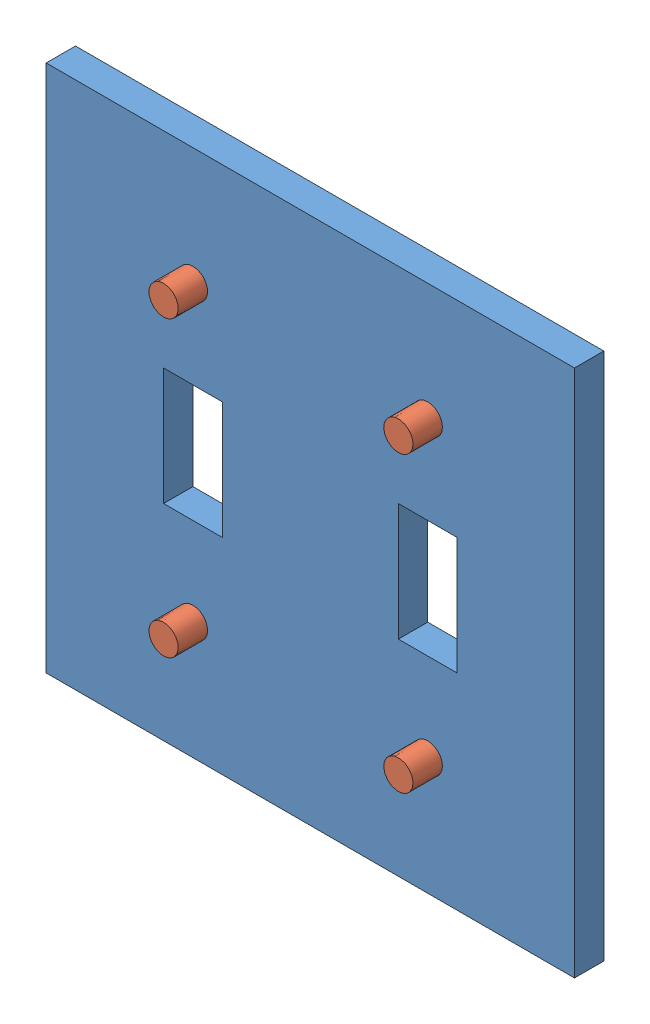
SolidWorks assembly switchplateassembly, configuration Default. Lengths in mm.
Overall size (114.3 114.3 19.05).
5 component instances, 2 part files, 8 mates.
Components (placement in the parent):
- switchplate-2: switchplate [Default] at (-12.9603 3.888 82.8112) size (114.3 114.3 6.35)
- fastener-1: fastener [Default] at (14.7933 100.83 76.4612) x (-0.318546 -0.947907 0) z (0 0 1) size (12.7 12.7 19.05)
- fastener-2: fastener [Default] at (66.8696 37.8464 76.4612) x (-0.459707 -0.88807 0) z (0 0 1) size (12.7 12.7 19.05)
- fastener-3: fastener [Default] at (23.1681 21.4474 76.4612) x (0.272622 0.962121 0) z (0 0 1) size (12.7 12.7 19.05)
- fastener-4: fastener [Default] at (69.3542 83.8108 76.4612) x (0.725412 0.688315 0) z (0 0 1) size (12.7 12.7 19.05)
Mates (geometry in assembly coordinates):
- Concentric1: concentric anti-aligned: cylinder of switchplate-2 through (69.5897 92.788 82.8112) axis (0 0 1) radius 3.175; cylinder of fastener-4 through (69.5897 92.788 95.5112) axis (0 0 -1) radius 3.175
- Coincident1: coincident anti-aligned: plane of switchplate-2 through (-12.9603 3.888 82.8112) normal (0 0 -1); plane of fastener-4 through (69.3542 83.8108 82.8112) normal (0 0 1)
- Concentric2: concentric anti-aligned: cylinder of switchplate-2 through (18.7897 29.288 82.8112) axis (0 0 1) radius 3.175; cylinder of fastener-3 through (18.7897 29.288 95.5112) axis (0 0 -1) radius 3.175
- Coincident2: coincident anti-aligned: plane of switchplate-2 through (-12.9603 3.888 82.8112) normal (0 0 -1); plane of fastener-3 through (23.1681 21.4474 82.8112) normal (0 0 1)
- Concentric3: concentric anti-aligned: cylinder of switchplate-2 through (18.7897 92.788 82.8112) axis (0 0 1) radius 3.175; cylinder of fastener-1 through (18.7897 92.788 95.5112) axis (0 0 -1) radius 3.175
- Coincident3: coincident anti-aligned: plane of switchplate-2 through (-12.9603 3.888 82.8112) normal (0 0 -1); plane of fastener-1 through (14.7933 100.83 82.8112) normal (0 0 1)
- Concentric4: concentric anti-aligned: cylinder of switchplate-2 through (69.5897 29.288 82.8112) axis (0 0 1) radius 3.175; cylinder of fastener-2 through (69.5897 29.288 95.5112) axis (0 0 -1) radius 3.175
- Coincident4: coincident anti-aligned: plane of switchplate-2 through (-12.9603 3.888 82.8112) normal (0 0 -1); plane of fastener-2 through (66.8696 37.8464 82.8112) normal (0 0 1)
